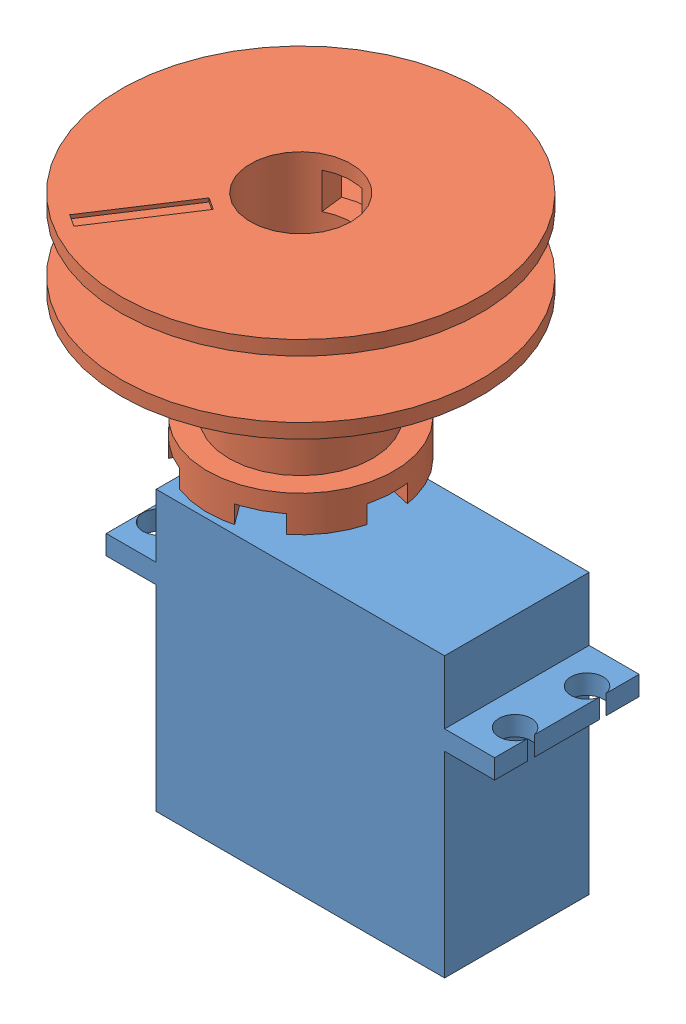
SolidWorks assembly motor_long, configuration ﾃﾞﾌｫﾙﾄ. Lengths in mm.
Overall size (75.45 74.5 73.44).
2 component instances, 2 part files, 8 mates.
Components (placement in the parent):
- FB5311M-1: FB5311M [ﾃﾞﾌｫﾙﾄ] at origin size (54 44.25 20.1)
- servo_horn_long-1: servo_horn_long [ﾃﾞﾌｫﾙﾄ] at (-10 42.5 0) x (-0.837169 0 -0.546944) z (0 1 0) size (50 57.04 32)
Mates (geometry in assembly coordinates):
- 同心円1: concentric aligned: cylinder of FB5311M-1 through (-10 52.7353 0) axis (0 -1 0) radius 3; cylinder of pulley-1 through (-10 59.25 0) axis (0 -1 0) radius 25
- 同心円2: concentric anti-aligned: cylinder of FB5311M-1 through (-10 52.7353 0) axis (0 -1 0) radius 3; cylinder of pulley_spacer-1 through (-10 44.25 0) axis (0 1 0) radius 10
- 一致2: coincident anti-aligned: plane of FB5311M-1 through (0 44.25 0) normal (0 1 0); circle of pulley_spacer-1
- 一致3: coincident anti-aligned: plane of pulley-1 through (-10 59.25 0) normal (0 -1 0); plane of pulley_spacer-1 through (-10 59.25 0) normal (0 1 0)
- 同心円3: concentric aligned: cylinder of FB5311M-1 through (-10 52.7353 0) axis (0 -1 0) radius 3; cylinder of servo_horn-1 through (-10 47.5 0) axis (0 -1 0) radius 13
- 距離1: distance = 6.2 mm anti-aligned: plane of FB5311M-1 through (0 38.8 0) normal (0 1 0); plane of servo_horn-1 through (-23.4795 45 -0.7436) normal (0 -1 0)
- 同心円4: concentric aligned: cylinder of FB5311M-1 through (-10 52.7353 0) axis (0 -1 0) radius 3; cylinder of servo_horn_long-1 through (-10 47.5 0) axis (0 -1 0) radius 13
- 距離2: distance = 6.2 mm anti-aligned: plane of FB5311M-1 through (0 38.8 0) normal (0 1 0); plane of servo_horn_long-1 through (-23.4795 45 -0.7436) normal (0 -1 0)
